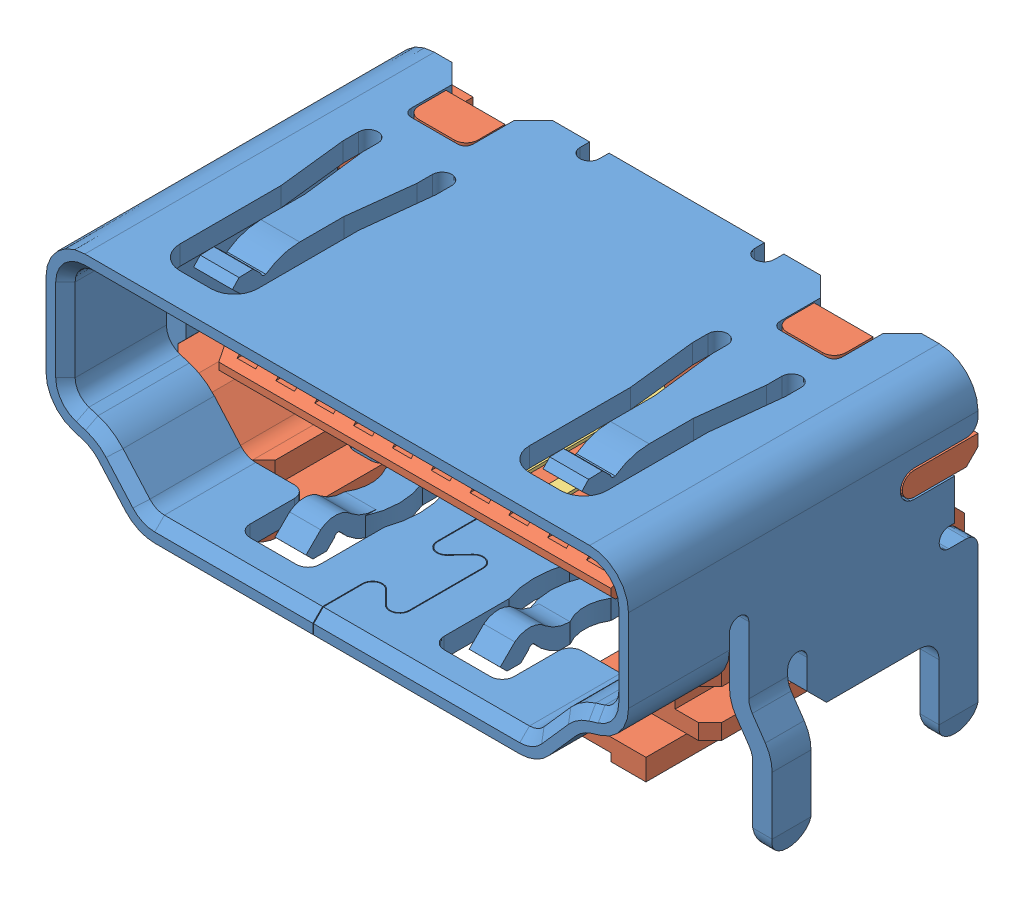
SolidWorks assembly raspberry_pi_B+_(HDMI_socket), configuration Default. Lengths in mm.
Overall size (16.2 8 9.9).
21 component instances, 4 part files, 0 mates.
Components (placement in the parent):
- raspberry_pi__HDMI_socket_cover-1: raspberry_pi__HDMI_socket_cover [Default] at (-20 0 0) size (16.2 8 9)
- raspberry_pi__HDMI_socket_inside-1: raspberry_pi__HDMI_socket_inside [Default] at (-20 0 0) size (15 6.1 7.6)
- raspberry_pi__HDMI_socket_large_pin-1: raspberry_pi__HDMI_socket_large_pin [Valor predeterminado] at (-201.7661 0.45 76.5103) x (0 0 -1) z (0 -1 0) size (7.55 0.65 3.84)
- raspberry_pi__HDMI_socket_small_pin-1: raspberry_pi__HDMI_socket_small_pin [Valor predeterminado] at (-202.2661 -0.25 76.5103) x (0 0 -1) z (0 -1 0) size (7.55 0.65 3.08)
- raspberry_pi__HDMI_socket_large_pin-2: raspberry_pi__HDMI_socket_large_pin [Valor predeterminado] at (-202.7661 0.45 76.5103) x (0 0 -1) z (0 -1 0) size (7.55 0.65 3.84)
- raspberry_pi__HDMI_socket_large_pin-3: raspberry_pi__HDMI_socket_large_pin [Valor predeterminado] at (-203.7661 0.45 76.5103) x (0 0 -1) z (0 -1 0) size (7.55 0.65 3.84)
- raspberry_pi__HDMI_socket_large_pin-4: raspberry_pi__HDMI_socket_large_pin [Valor predeterminado] at (-204.7661 0.45 76.5103) x (0 0 -1) z (0 -1 0) size (7.55 0.65 3.84)
- raspberry_pi__HDMI_socket_large_pin-5: raspberry_pi__HDMI_socket_large_pin [Valor predeterminado] at (-205.7661 0.45 76.5103) x (0 0 -1) z (0 -1 0) size (7.55 0.65 3.84)
- raspberry_pi__HDMI_socket_large_pin-6: raspberry_pi__HDMI_socket_large_pin [Valor predeterminado] at (-206.7661 0.45 76.5103) x (0 0 -1) z (0 -1 0) size (7.55 0.65 3.84)
- raspberry_pi__HDMI_socket_large_pin-7: raspberry_pi__HDMI_socket_large_pin [Valor predeterminado] at (-207.7661 0.45 76.5103) x (0 0 -1) z (0 -1 0) size (7.55 0.65 3.84)
- raspberry_pi__HDMI_socket_large_pin-8: raspberry_pi__HDMI_socket_large_pin [Valor predeterminado] at (-208.7661 0.45 76.5103) x (0 0 -1) z (0 -1 0) size (7.55 0.65 3.84)
- raspberry_pi__HDMI_socket_large_pin-9: raspberry_pi__HDMI_socket_large_pin [Valor predeterminado] at (-209.7661 0.45 76.5103) x (0 0 -1) z (0 -1 0) size (7.55 0.65 3.84)
- raspberry_pi__HDMI_socket_large_pin-10: raspberry_pi__HDMI_socket_large_pin [Valor predeterminado] at (-210.7661 0.45 76.5103) x (0 0 -1) z (0 -1 0) size (7.55 0.65 3.84)
- raspberry_pi__HDMI_socket_small_pin-2: raspberry_pi__HDMI_socket_small_pin [Valor predeterminado] at (-203.2661 -0.25 76.5103) x (0 0 -1) z (0 -1 0) size (7.55 0.65 3.08)
- raspberry_pi__HDMI_socket_small_pin-3: raspberry_pi__HDMI_socket_small_pin [Valor predeterminado] at (-204.2661 -0.25 76.5103) x (0 0 -1) z (0 -1 0) size (7.55 0.65 3.08)
- raspberry_pi__HDMI_socket_small_pin-4: raspberry_pi__HDMI_socket_small_pin [Valor predeterminado] at (-205.2661 -0.25 76.5103) x (0 0 -1) z (0 -1 0) size (7.55 0.65 3.08)
- raspberry_pi__HDMI_socket_small_pin-5: raspberry_pi__HDMI_socket_small_pin [Valor predeterminado] at (-206.2661 -0.25 76.5103) x (0 0 -1) z (0 -1 0) size (7.55 0.65 3.08)
- raspberry_pi__HDMI_socket_small_pin-6: raspberry_pi__HDMI_socket_small_pin [Valor predeterminado] at (-207.2661 -0.25 76.5103) x (0 0 -1) z (0 -1 0) size (7.55 0.65 3.08)
- raspberry_pi__HDMI_socket_small_pin-7: raspberry_pi__HDMI_socket_small_pin [Valor predeterminado] at (-208.2661 -0.25 76.5103) x (0 0 -1) z (0 -1 0) size (7.55 0.65 3.08)
- raspberry_pi__HDMI_socket_small_pin-8: raspberry_pi__HDMI_socket_small_pin [Valor predeterminado] at (-209.2661 -0.25 76.5103) x (0 0 -1) z (0 -1 0) size (7.55 0.65 3.08)
- raspberry_pi__HDMI_socket_small_pin-9: raspberry_pi__HDMI_socket_small_pin [Valor predeterminado] at (-210.2661 -0.25 76.5103) x (0 0 -1) z (0 -1 0) size (7.55 0.65 3.08)
